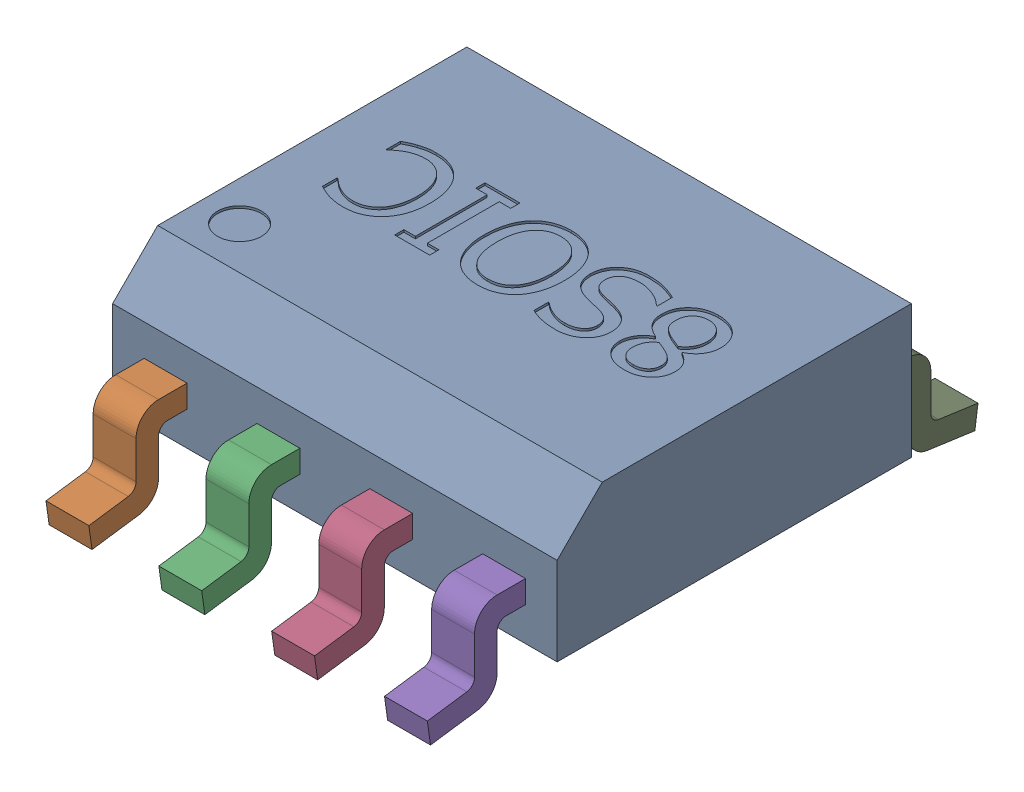
SolidWorks assembly 8SIOC.step, configuration Default. Lengths in mm.
Overall size (5 1.95 6.2).
9 component instances, 2 part files, 0 mates.
Components (placement in the parent):
- 8SOIC_BODY.step-1: 8SOIC_BODY.step [Default] at origin size (5 1.5 3.99)
- 8SOIC_PIN.step-1: 8SOIC_PIN.step [Default] at (-1.905 0.508 1.9939) x (0 0 1) z (-1 0 0) size (1.1 1.09 0.48)
- 8SOIC_PIN.step-2: 8SOIC_PIN.step [Default] at (-0.635 0.508 1.9939) x (0 0 1) z (-1 0 0) size (1.1 1.09 0.48)
- 8SOIC_PIN.step-3: 8SOIC_PIN.step [Default] at (0.635 0.508 1.9939) x (0 0 1) z (-1 0 0) size (1.1 1.09 0.48)
- 8SOIC_PIN.step-4: 8SOIC_PIN.step [Default] at (1.905 0.508 1.9939) x (0 0 1) z (-1 0 0) size (1.1 1.09 0.48)
- 8SOIC_PIN.step-5: 8SOIC_PIN.step [Default] at (-1.905 0.508 -1.9939) x (0 0 -1) z (1 0 0) size (1.1 1.09 0.48)
- 8SOIC_PIN.step-6: 8SOIC_PIN.step [Default] at (-0.635 0.508 -1.9939) x (0 0 -1) z (1 0 0) size (1.1 1.09 0.48)
- 8SOIC_PIN.step-7: 8SOIC_PIN.step [Default] at (0.635 0.508 -1.9939) x (0 0 -1) z (1 0 0) size (1.1 1.09 0.48)
- 8SOIC_PIN.step-8: 8SOIC_PIN.step [Default] at (1.905 0.508 -1.9939) x (0 0 -1) z (1 0 0) size (1.1 1.09 0.48)
